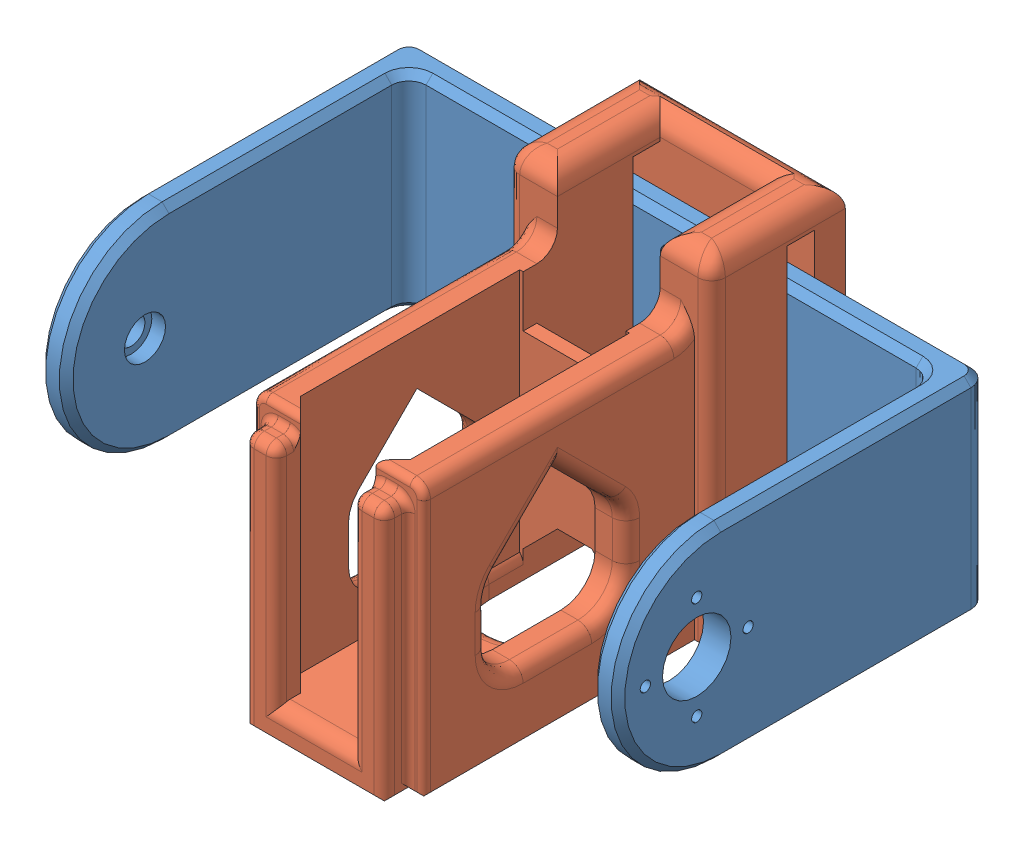
SolidWorks assembly Gemini_V3_EVT_Holder, configuration Default. Lengths in mm.
Overall size (170.5 90 123).
2 component instances, 2 part files, 0 mates.
Components (placement in the parent):
- DUT_Bridge-1: DUT_Bridge [Default] at (0 0 -85) x (1 0 0) z (0 -1 0) size (170.5 108 60)
- gemini_v3_EVT_holder_v2-1: gemini_v3_EVT_holder_v2 [Default] at (3.85 -153 -55) x (0 0 -1) z (1 0 0) size (125 100 60)
